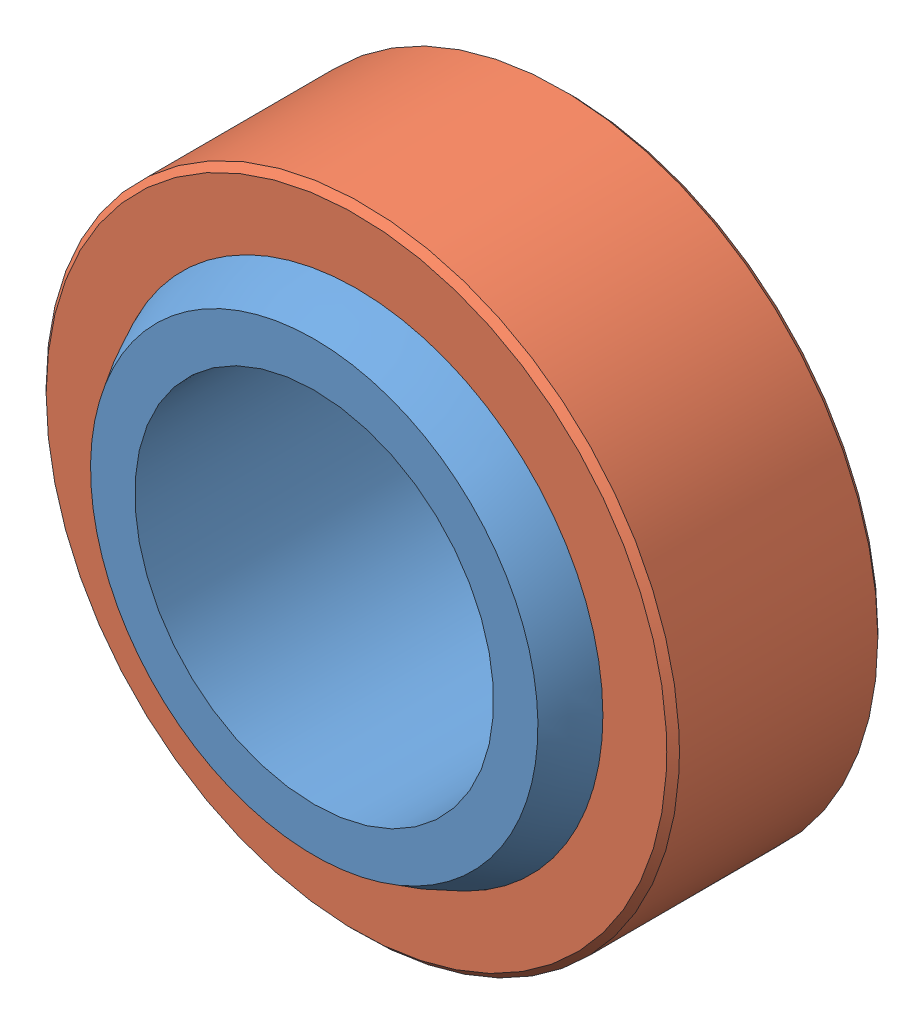
SolidWorks assembly SphericalBearingGE17C, configuration Default. Lengths in mm.
Overall size (30 32.6 22.58).
2 component instances, 2 part files, 1 mates.
Components (placement in the parent):
- SphericalBearingBallGE17C-1: SphericalBearingBallGE17C [Default] at origin size (25.4 32.6 22.58)
- SphericalBeaingRaceGE17C-1: SphericalBeaingRaceGE17C [Default] at origin size (30 30 10)
Mates (geometry in assembly coordinates):
- Concentric1: concentric: sphere of ?; unknown of ?
